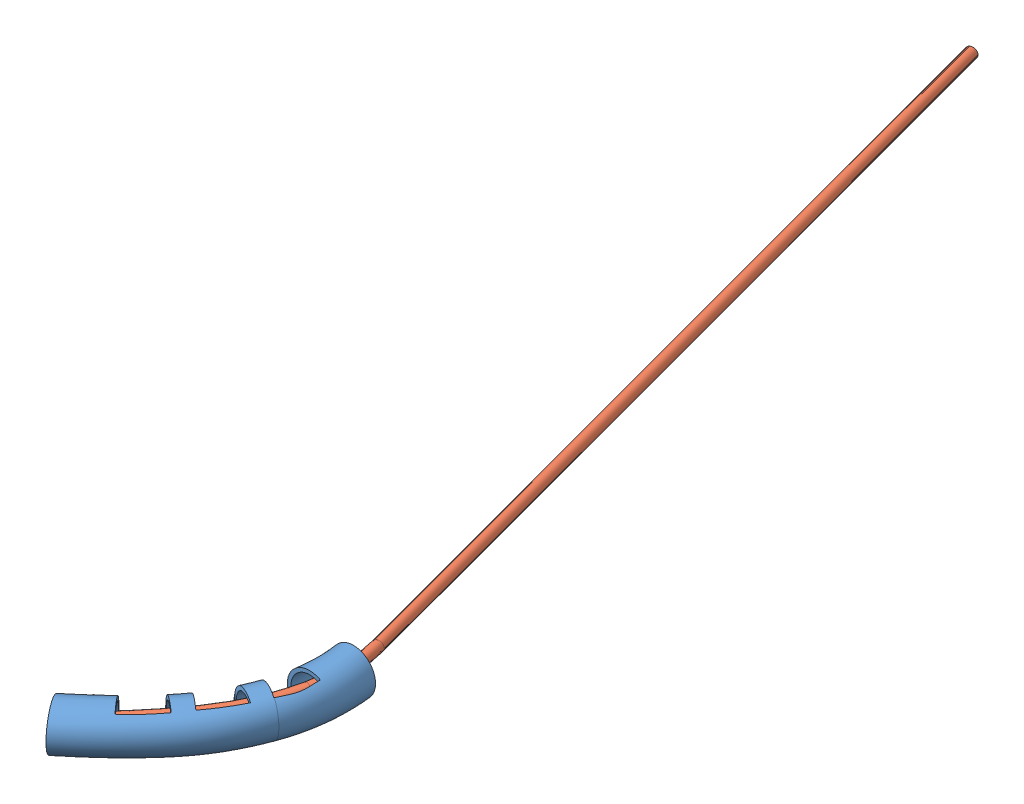
SolidWorks assembly cable + square joint_curve 2 assem, configuration Default. Lengths in mm.
Overall size (18.55 1.31 29.8).
2 component instances, 2 part files, 2 mates.
Components (placement in the parent):
- Arushri_Tube_SquareJoint_curve 2-1: Arushri_Tube_SquareJoint_curve 2 [Default] at (3.9357 4.1267 4.0971) size (4.02 1.31 16.37)
- cable_curve2-1: cable_curve2 [Default] at (1.1737 4.1267 8.6296) x (-0.396928 0 -0.91785) z (0 1 0) size (27.85 8.17 0.5)
Mates (geometry in assembly coordinates):
- Concentric1: concentric anti-aligned: circle of Arushri_Tube_SquareJoint_curve 2-1; circle of cable_curve2-1
- Coincident3: coincident aligned: circle of Arushri_Tube_SquareJoint_curve 2-1; circle of cable_curve2-1
